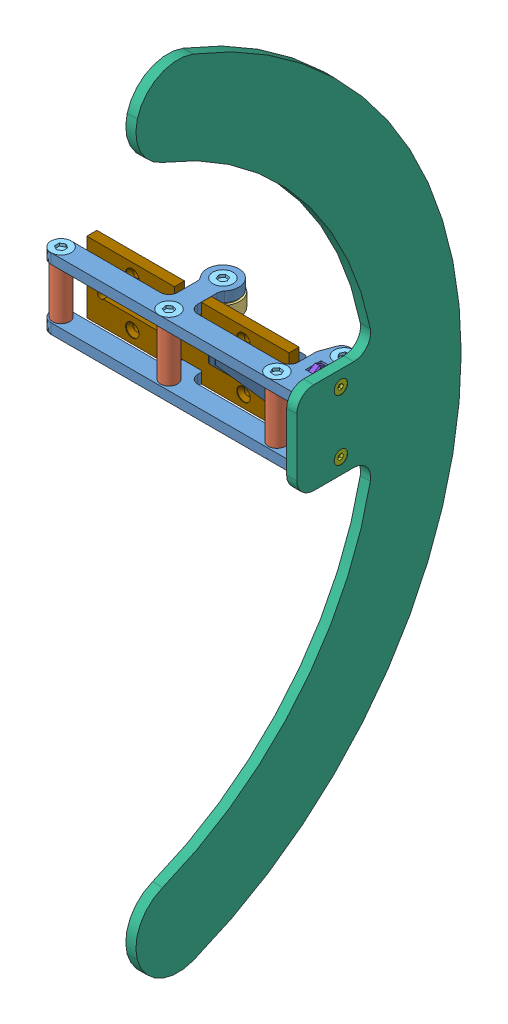
SolidWorks assembly shifter assembly, configuration Default. Lengths in mm.
Overall size (79 234.52 96.49).
28 component instances, 10 part files, 61 mates.
Components (placement in the parent):
- arm-1: arm [Bottom] at origin size (77.3 3 23.76)
- arm-2: arm [Top] at (0 18 0) size (77.3 3 23.76)
- standoff-15mm-1: standoff-15mm [Default] at (-32 3 16) x (0.079826 0 0.996809) z (-0.996809 0 0.079826) size (5 15 5)
- standoff-15mm-2: standoff-15mm [Default] at (0 3 16) x (0.266249 0 0.963904) z (-0.963904 0 0.266249) size (5 15 5)
- standoff-15mm-3: standoff-15mm [Default] at (32 3 16) x (0.46778 0 0.883845) z (-0.883845 0 0.46778) size (5 15 5)
- standoff-15mm-4: standoff-15mm [Default] at (38 3 2) x (0.661946 0 0.749552) z (-0.749552 0 0.661946) size (5 15 5)
- bearing-5x10x4-1: bearing-5x10x4 [Default] at (0 13.5 0) x (0.999569 0 0.029351) z (-0.029351 0 0.999569) size (10 4 10)
- bearing-spacer-1: bearing-spacer [Default] at (0 17.5 0) size (7.5 0.5 7.5)
- bearing-5x10x4-2: bearing-5x10x4 [Default] at (0 3.5 0) x (0.625763 0 0.780013) z (-0.780013 0 0.625763) size (10 4 10)
- bearing-spacer-2: bearing-spacer [Default] at (0 3 0) size (7.5 0.5 7.5)
- countersunk-screw-m3-8mm-1: countersunk-screw-m3-8mm [Default] at (-32 20.9995 16) x (0 -1 0) z (0 0 1) size (8 6 6)
- countersunk-screw-m3-8mm-2: countersunk-screw-m3-8mm [Default] at (0 20.9995 16) x (0 -1 0) z (0.188455 0 0.982082) size (8 6 6)
- countersunk-screw-m3-8mm-4: countersunk-screw-m3-8mm [Default] at (32 20.9995 16) x (0 -1 0) z (0.395734 0 0.918365) size (8 6 6)
- countersunk-screw-m3-8mm-6: countersunk-screw-m3-8mm [Default] at (38 20.9995 2) x (0 -1 0) z (0.6 0 0.8) size (8 6 6)
- countersunk-screw-m3-8mm-8: countersunk-screw-m3-8mm [Default] at (-32 0.0005 16) x (0 1 0) z (1 0 0) size (8 6 6)
- countersunk-screw-m3-8mm-10: countersunk-screw-m3-8mm [Default] at (0 0.0005 16) x (0 1 0) z (1 0 0) size (8 6 6)
- countersunk-screw-m3-8mm-12: countersunk-screw-m3-8mm [Default] at (32 0.0005 16) x (0 1 0) z (1 0 0) size (8 6 6)
- countersunk-screw-m3-8mm-14: countersunk-screw-m3-8mm [Default] at (38 0.0005 2) x (0 1 0) z (1 0 0) size (8 6 6)
- paddle-1: paddle [Default] at (41 10.5 98.3366) x (0 0 -1) z (0 -1 0) size (96.49 3 234.52)
- countersunk-screw-m2-8mm-1: countersunk-screw-m2-8mm [Default] at (43.9 19.5 9) x (-1 0 0) z (0 0 -1) size (8 4 4)
- countersunk-screw-m2-8mm-2: countersunk-screw-m2-8mm [Default] at (43.9 1.5 9) x (-1 0 0) z (0 0.158553 -0.987351) size (8 4 4)
- nut-m2-1: nut-m2 [Default] at (36 19.5 9) x (0 1 0) z (1 0 0) size (4.62 4 2)
- nut-m2-2: nut-m2 [Default] at (36 1.5 9) x (0 1 0) z (1 0 0) size (4.62 4 2)
- body-1: body [Default] at (-0.9411 10.5 6.4486) x (1 0 0) z (0 -1 0) size (60 3 21)
- switch-1: switch [Default] at (15.5589 10.5 5.0986) x (1 0 0) z (0 0 -1) size (28.06 6.35 15.08)
- standoff-15mm-5: standoff-15mm [Default] at (0 3 0) x (0.892707 0 0.450638) z (-0.450638 0 0.892707) size (5 15 5)
- countersunk-screw-m3-8mm-16: countersunk-screw-m3-8mm [Default] at (0 20.9995 0) x (0 -1 0) z (0.370156 0 0.92897) size (8 6 6)
- countersunk-screw-m3-8mm-18: countersunk-screw-m3-8mm [Default] at (0 0.0005 0) x (0 1 0) z (0.982082 0 0.188455) size (8 6 6)
Mates (geometry in assembly coordinates):
- Concentric1: concentric: cylinder of arm-1 through (-32.5 3 15.5) axis (0 -1 0) radius 1.5; cylinder of ? through (-32.5 23 15.5) axis (0 -1 0) radius 2.5
- Coincident1: coincident: plane of arm-1 through (0 3 0) normal (0 1 0); plane of ? through (-32.5 3 15.5) normal (0 -1 0)
- Concentric2: concentric: cylinder of arm-1 through (0 3 15.5) axis (0 -1 0) radius 1.5; cylinder of ? through (0 23 15.5) axis (0 -1 0) radius 2.5
- Coincident2: coincident: plane of arm-1 through (0 3 0) normal (0 1 0); plane of ? through (0 3 15.5) normal (0 -1 0)
- Coincident3: coincident: plane of arm-1 through (0 3 0) normal (0 1 0); plane of ? through (37.5 3 15.5) normal (0 -1 0)
- Concentric3: concentric: cylinder of arm-1 through (37.5 3 15.5) axis (0 -1 0) radius 1.5; cylinder of ? through (37.5 23 15.5) axis (0 -1 0) radius 2.5
- Coincident4: coincident: plane of arm-1 through (0 3 0) normal (0 1 0); plane of ? through (37.5 3 0.5) normal (0 -1 0)
- Concentric4: concentric: cylinder of arm-1 through (37.5 3 0.5) axis (0 -1 0) radius 1.5; cylinder of ? through (37.5 23 0.5) axis (0 -1 0) radius 2.5
- Concentric5: concentric: cylinder of arm-1 through (-32 3 16) axis (0 -1 0) radius 1.5; cylinder of arm-2 through (-32 21 16) axis (0 -1 0) radius 1.5
- Concentric6: concentric: cylinder of arm-1 through (38 3 2) axis (0 -1 0) radius 1.5; cylinder of arm-2 through (38 21 2) axis (0 -1 0) radius 1.5
- Coincident6: coincident: plane of ? through (-32.5 23 15.5) normal (0 1 0); plane of arm-2 through (0 23 0) normal (0 -1 0)
- Concentric7: concentric: cylinder of arm-1 through (-32 3 16) axis (0 -1 0) radius 1.5; cylinder of standoff-15mm-1 through (-32 18 16) axis (0 -1 0) radius 1.4
- Coincident7: coincident: plane of arm-1 through (0 3 0) normal (0 1 0); plane of standoff-15mm-1 through (-32 3 16) normal (0 -1 0)
- Coincident8: coincident: plane of arm-2 through (0 18 0) normal (0 -1 0); plane of standoff-15mm-1 through (-32 18 16) normal (0 1 0)
- Concentric8: concentric: cylinder of arm-1 through (0 3 16) axis (0 -1 0) radius 1.5; cylinder of standoff-15mm-2 through (0 18 16) axis (0 -1 0) radius 1.4
- Coincident9: coincident: plane of arm-1 through (0 3 0) normal (0 1 0); plane of standoff-15mm-2 through (0 3 16) normal (0 -1 0)
- Coincident10: coincident: plane of arm-1 through (0 3 0) normal (0 1 0); plane of standoff-15mm-3 through (32 3 16) normal (0 -1 0)
- Coincident11: coincident: plane of arm-1 through (0 3 0) normal (0 1 0); plane of standoff-15mm-4 through (38 3 2) normal (0 -1 0)
- Concentric10: concentric: cylinder of arm-1 through (38 3 2) axis (0 -1 0) radius 1.5; cylinder of standoff-15mm-4 through (38 18 2) axis (0 -1 0) radius 1.4
- Concentric11: concentric: cylinder of arm-2 through (0 21 0) axis (0 -1 0) radius 2.5; cylinder of ? through (0 20.3846 0) axis (0 -1 0) radius 1.4
- Concentric12: concentric: cylinder of ? through (0 20.3846 0) axis (0 -1 0) radius 2.5; cylinder of bearing-5x10x4-1 through (0 17.5 0) axis (0 -1 0) radius 2.5
- Concentric13: concentric: cylinder of ? through (0 20.3846 0) axis (0 -1 0) radius 2.5; cylinder of bearing-spacer-1 through (0 18 0) axis (0 -1 0) radius 2.75
- Coincident13: coincident: plane of arm-2 through (0 18 0) normal (0 -1 0); plane of bearing-spacer-1 through (0 18 0) normal (0 1 0)
- Coincident14: coincident: plane of bearing-5x10x4-1 through (0 17.5 0) normal (0 1 0); plane of bearing-spacer-1 through (0 17.5 0) normal (0 -1 0)
- Concentric14: concentric: cylinder of ? through (0 20.3846 0) axis (0 -1 0) radius 2.5; cylinder of bearing-5x10x4-2 through (0 7.5 0) axis (0 -1 0) radius 2.5
- Concentric16: concentric: cylinder of ? through (0 20.3846 0) axis (0 -1 0) radius 2.5; cylinder of bearing-spacer-2 through (0 3.5 0) axis (0 -1 0) radius 2.75
- Coincident15: coincident: plane of arm-1 through (0 3 0) normal (0 1 0); plane of bearing-spacer-2 through (0 3 0) normal (0 -1 0)
- Coincident16: coincident: plane of bearing-5x10x4-2 through (0 3.5 0) normal (0 -1 0); plane of bearing-spacer-2 through (0 3.5 0) normal (0 1 0)
- Coincident17: coincident: cone of arm-2 through (-32 20.8 16) axis (0 -1 0); cone of countersunk-screw-m3-8mm-1 through (-32 19.2995 16) axis (0 -1 0)
- Coincident18: coincident: cone of arm-2 through (0 20.8 16) axis (0 -1 0); cone of countersunk-screw-m3-8mm-2 through (0 19.2995 16) axis (0 -1 0)
- Coincident20: coincident: cone of arm-2 through (38 20.8 2) axis (0 -1 0); cone of countersunk-screw-m3-8mm-6 through (38 19.2995 2) axis (0 -1 0)
- Coincident21: coincident: cone of arm-1 through (-32 0.2 16) axis (0 1 0); cone of countersunk-screw-m3-8mm-8 through (-32 1.7005 16) axis (0 1 0)
- Coincident22: coincident: cone of arm-1 through (0 0.2 16) axis (0 1 0); cone of countersunk-screw-m3-8mm-10 through (0 1.7005 16) axis (0 1 0)
- Coincident24: coincident: cone of arm-1 through (38 0.2 2) axis (0 1 0); cone of countersunk-screw-m3-8mm-14 through (38 1.7005 2) axis (0 1 0)
- Coincident25: coincident: plane of arm-2 through (41 21 0) normal (1 0 0); plane of paddle-1 through (41 10.5 98.3366) normal (-1 0 0)
- Coincident26: coincident: plane of arm-1 through (41 3 0) normal (1 0 0); plane of paddle-1 through (41 10.5 98.3366) normal (-1 0 0)
- Concentric18: concentric: line of arm-1 through (38 1.5 9) axis (1 0 0); cylinder of paddle-1 through (44 1.5 9) axis (-1 0 0) radius 1
- Concentric19: concentric: line of arm-2 through (38 19.5 9) axis (1 0 0); cylinder of paddle-1 through (44 19.5 9) axis (-1 0 0) radius 1
- Coincident27: coincident: cone of paddle-1 through (43.8 19.5 9) axis (-1 0 0); cone of countersunk-screw-m2-8mm-1 through (42.8 19.5 9) axis (-1 0 0)
- Coincident28: coincident: cone of paddle-1 through (43.8 1.5 9) axis (-1 0 0); cone of countersunk-screw-m2-8mm-2 through (42.8 1.5 9) axis (-1 0 0)
- Concentric20: concentric: cylinder of countersunk-screw-m2-8mm-1 through (46.1818 19.5 9) axis (1 0 0) radius 1; cylinder of nut-m2-1 through (38 19.5 9) axis (-1 0 0) radius 1
- Coincident29: coincident: plane of arm-2 through (38 21 0) normal (-1 0 0); plane of nut-m2-1 through (38 19.5 9) normal (1 0 0)
- Parallel1: parallel: plane of arm-2 through (0 21 6.7) normal (0 0 1); plane of nut-m2-1 through (38 20.6547 11) normal (0 0 1)
- Concentric21: concentric: cylinder of countersunk-screw-m2-8mm-2 through (46.1818 1.5 9) axis (1 0 0) radius 1; cylinder of nut-m2-2 through (38 1.5 9) axis (-1 0 0) radius 1
- Coincident31: coincident: plane of arm-1 through (38 3 0) normal (-1 0 0); plane of nut-m2-2 through (38 1.5 9) normal (1 0 0)
- Parallel2: parallel: plane of arm-1 through (0 3 6.7) normal (0 0 1); plane of nut-m2-2 through (38 2.6547 11) normal (0 0 1)
- Width2: width: plane of body-1 through (-0.9411 13.775 9.4486) normal (0 -1 0); plane of body-1 through (-0.9411 7.225 9.4486) normal (0 1 0); plane of switch-1 through (15.5589 7.325 5.4495) normal (0 -1 0); plane of switch-1 through (15.5589 13.675 5.4495) normal (0 1 0)
- Width3: width: plane of body-1 through (5.5589 10.5 9.4486) normal (1 0 0); plane of body-1 through (25.5589 10.5 9.4486) normal (-1 0 0); plane of switch-1 through (25.4839 7.325 5.4495) normal (1 0 0); plane of switch-1 through (5.6339 7.325 5.4495) normal (-1 0 0)
- Width4: width: plane of arm-2 through (0 21 0) normal (0 1 0); plane of arm-1 through (0 0 0) normal (0 -1 0); plane of body-1 through (-0.9411 21 9.4486) normal (0 1 0); plane of body-1 through (-0.9411 0 9.4486) normal (0 -1 0)
- Concentric22: concentric: cylinder of arm-1 through (0 3 0) axis (0 -1 0) radius 1.5; cylinder of standoff-15mm-5 through (0 18 0) axis (0 -1 0) radius 1.4
- Coincident32: coincident: plane of arm-1 through (0 3 0) normal (0 1 0); plane of standoff-15mm-5 through (0 3 0) normal (0 -1 0)
- Concentric23: concentric: cylinder of bearing-spacer-2 through (0 3.5 0) axis (0 -1 0) radius 2.75; cylinder of standoff-15mm-5 through (0 18 0) axis (0 -1 0) radius 2.5
- Concentric24: concentric: cylinder of bearing-5x10x4-2 through (0 7.5 0) axis (0 -1 0) radius 2.5; cylinder of standoff-15mm-5 through (0 18 0) axis (0 -1 0) radius 2.5
- Concentric25: concentric: cylinder of bearing-spacer-1 through (0 18 0) axis (0 -1 0) radius 2.75; cylinder of standoff-15mm-5 through (0 18 0) axis (0 -1 0) radius 2.5
- Concentric26: concentric: cylinder of bearing-5x10x4-1 through (0 17.5 0) axis (0 -1 0) radius 2.5; cylinder of standoff-15mm-5 through (0 18 0) axis (0 -1 0) radius 2.5
- Coincident33: coincident: cone of arm-2 through (0 20.8 0) axis (0 -1 0); cone of countersunk-screw-m3-8mm-16 through (0 19.2995 0) axis (0 -1 0)
- Coincident34: coincident: cone of arm-1 through (0 0.2 0) axis (0 1 0); cone of countersunk-screw-m3-8mm-18 through (0 1.7005 0) axis (0 1 0)
- Concentric27: concentric: cylinder of arm-1 through (32 3 16) axis (0 -1 0) radius 1.5; cylinder of standoff-15mm-3 through (32 18 16) axis (0 -1 0) radius 1.4
- Coincident35: coincident: cone of arm-2 through (32 20.8 16) axis (0 -1 0); cone of countersunk-screw-m3-8mm-4 through (32 19.2995 16) axis (0 -1 0)
- Coincident36: coincident: cone of arm-1 through (32 0.2 16) axis (0 1 0); cone of countersunk-screw-m3-8mm-12 through (32 1.7005 16) axis (0 1 0)
- Coincident37: coincident: plane of body-1 through (-0.9411 10.5 9.4486) normal (0 0 1); plane of switch-1 through (15.5589 7.325 9.4486) normal (0 0 1)
